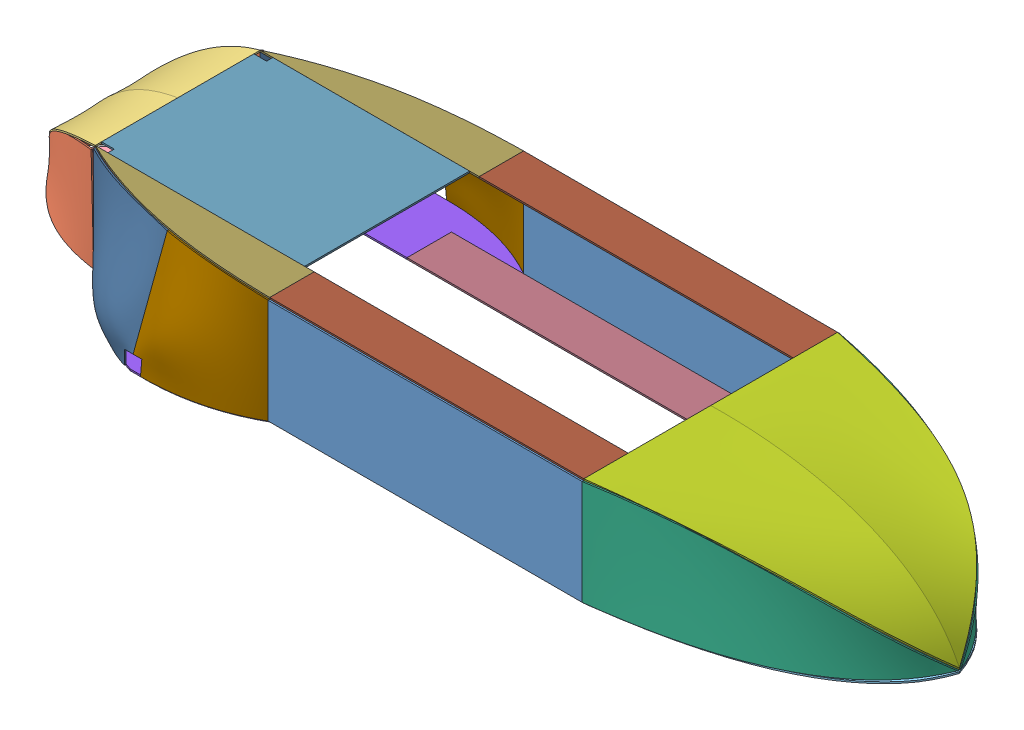
SolidWorks assembly body panels final, configuration Default. Lengths in mm.
Overall size (3694.44 535.04 1245.02).
21 component instances, 14 part files, 1 mates.
Components (placement in the parent):
- Part27-1: Part27 [Default] at (-358.8529 1808.8371 3370.6746) size (1257.3 419.1 6.35)
- Boss-Extrude11-1: Boss-Extrude11 [Default] at (682.7361 457.8434 2657.5682) size (516.43 425.6 692.74)
- Boss-Extrude13-1: Boss-Extrude13 [Default] at (682.7361 457.8434 2657.5682) size (523.73 421.97 664.38)
- Boss-Extrude14-1: Boss-Extrude14 [Default] at (682.7361 457.8434 2657.5682) size (482.6 6.35 330.2)
- Boss-Extrude15-1: Boss-Extrude15 [Default] at (682.7361 457.8434 2657.5682) size (995.11 6.35 508)
- Boss-Extrude16-1: Boss-Extrude16 [Default] at (682.7361 457.8434 2657.5682) size (1064.61 535.04 1037.24)
- Boss-Extrude17-1: Boss-Extrude17 [Default] at (682.7361 457.8434 2657.5682) size (1051.95 430.69 1027.1)
- Boss-Extrude18-1: Boss-Extrude18 [Default] at (682.7361 457.8434 2657.5682) size (876.3 6.35 283.09)
- Boss-Extrude20-1: Boss-Extrude20 [Default] at (682.7361 457.8434 2657.5682) size (462.61 454 1239.76)
- Boss-Extrude21-1: Boss-Extrude21 [Default] at (682.736 457.8434 2657.5681) size (498.64 451.05 1245.02)
- Boss-Extrude5-1: Boss-Extrude5 [Default] at (682.7361 457.8434 2657.5682) size (1257.3 6.35 177.8)
- Boss-Extrude7-1: Boss-Extrude7 [Default] at (682.915 457.8434 2657.4724) size (876.48 6.35 177.9)
- Boss-Extrude8-1: Boss-Extrude8 [Default] at (682.7361 457.8434 2657.5682) size (1545.9 6.35 177.8)
- Boss-Extrude8-2: Boss-Extrude8 [Default] at (682.7361 457.8434 3495.7682) size (1545.9 6.35 177.8)
- Boss-Extrude5-2: Boss-Extrude5 [Default] at (682.7361 457.8434 3495.7682) size (1257.3 6.35 177.8)
- Boss-Extrude7-2: Boss-Extrude7 [Default] at (682.915 4107.2277 5560.5732) x (1 0 0) z (0 0 -1) size (876.48 6.35 177.9)
- Boss-Extrude18-2: Boss-Extrude18 [Default] at (682.7361 3256.3276 5560.4773) x (1 0 0) z (0 0 -1) size (876.3 6.35 283.09)
- Boss-Extrude15-2: Boss-Extrude15 [Default] at (682.7361 3256.3276 5560.4773) x (1 0 0) z (0 0 -1) size (995.11 6.35 508)
- Boss-Extrude14-2: Boss-Extrude14 [Default] at (682.7361 3256.3276 5560.4773) x (1 0 0) z (0 0 -1) size (482.6 6.35 330.2)
- Part27-2: Part27 [Default] at (-358.8529 1808.8371 4393.0246) size (1257.3 419.1 6.35)
- Part5^body panels final-1: Part5^body panels final [Default] at origin size (838.2 6.35 660.49) (virtual)
Mates (geometry in assembly coordinates):
- Coincident15: coincident: point of Boss-Extrude13-1; point of Boss-Extrude7-1
